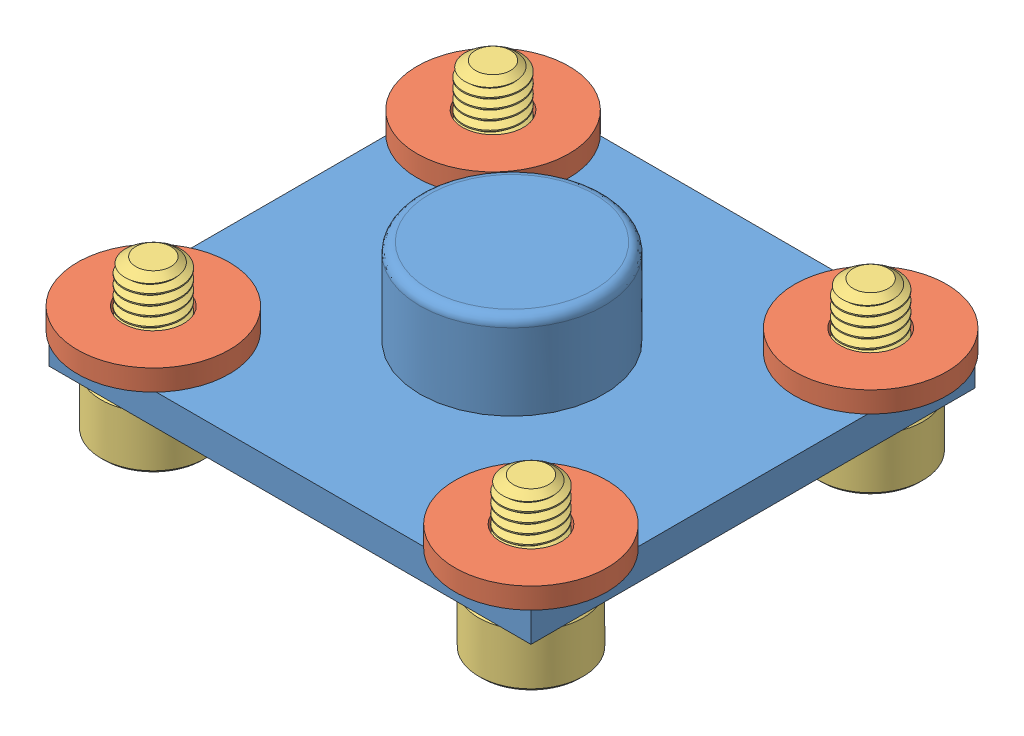
SolidWorks assembly Micro_withScrews, configuration Default. Lengths in mm.
Overall size (30.12 9.31 28.12).
9 component instances, 3 part files, 16 mates.
Components (placement in the parent):
- Micro-1: Micro [Default] at (8.9405 9.1432 20.4797) size (25.4 6.17 23.4)
- 95610A330_NYLON FLAT WASHER-2: 95610A330_NYLON FLAT WASHER [95610A330] at (18.8905 10.7832 29.4297) x (0.911056 0 -0.412283) z (0 1 0) size (8 8 1.1)
- 95610A330_NYLON FLAT WASHER-3: 95610A330_NYLON FLAT WASHER [95610A330] at (-1.0095 10.7832 29.4297) x (0.995756 0 -0.092036) z (0 1 0) size (8 8 1.1)
- 95610A330_NYLON FLAT WASHER-4: 95610A330_NYLON FLAT WASHER [95610A330] at (18.8905 10.7832 11.5297) x (0.992858 0 -0.119302) z (0 1 0) size (8 8 1.1)
- 95610A330_NYLON FLAT WASHER-5: 95610A330_NYLON FLAT WASHER [95610A330] at (-1.0095 10.7832 11.5297) x (0.963535 0 -0.267582) z (0 1 0) size (8 8 1.1)
- 91290A110_BLACK-OXIDE CLASS 12.9 SOCKET HEAD CAP SCREW-1: 91290A110_BLACK-OXIDE CLASS 12.9 SOCKET HEAD CAP SCREW [91290A110] at (-1.0095 14.1432 11.5297) x (0.69601 0 0.718032) z (0 1 0) size (5.5 5.5 8.18)
- 91290A110_BLACK-OXIDE CLASS 12.9 SOCKET HEAD CAP SCREW-2: 91290A110_BLACK-OXIDE CLASS 12.9 SOCKET HEAD CAP SCREW [91290A110] at (-1.0095 14.1432 29.4297) x (0.69601 0 0.718032) z (0 1 0) size (5.5 5.5 8.18)
- 91290A110_BLACK-OXIDE CLASS 12.9 SOCKET HEAD CAP SCREW-3: 91290A110_BLACK-OXIDE CLASS 12.9 SOCKET HEAD CAP SCREW [91290A110] at (18.8905 14.1432 11.5297) x (0.69601 0 0.718032) z (0 1 0) size (5.5 5.5 8.18)
- 91290A110_BLACK-OXIDE CLASS 12.9 SOCKET HEAD CAP SCREW-4: 91290A110_BLACK-OXIDE CLASS 12.9 SOCKET HEAD CAP SCREW [91290A110] at (18.8905 14.1432 29.4297) x (0.69601 0 0.718032) z (0 1 0) size (5.5 5.5 8.18)
Mates (geometry in assembly coordinates):
- Coincident1: coincident anti-aligned: plane of Micro-1 through (8.9405 10.7832 20.4797) normal (0 1 0); plane of 95610A330_NYLON FLAT WASHER-5 through (-1.0095 10.7832 11.5297) normal (0 -1 0)
- Coincident2: coincident anti-aligned: plane of Micro-1 through (8.9405 10.7832 20.4797) normal (0 1 0); plane of 95610A330_NYLON FLAT WASHER-3 through (-1.0095 10.7832 29.4297) normal (0 -1 0)
- Coincident3: coincident anti-aligned: plane of Micro-1 through (8.9405 10.7832 20.4797) normal (0 1 0); plane of 95610A330_NYLON FLAT WASHER-4 through (18.8905 10.7832 11.5297) normal (0 -1 0)
- Coincident4: coincident anti-aligned: plane of Micro-1 through (8.9405 10.7832 20.4797) normal (0 1 0); plane of 95610A330_NYLON FLAT WASHER-2 through (18.8905 10.7832 29.4297) normal (0 -1 0)
- Concentric1: concentric anti-aligned: cylinder of Micro-1 through (18.8905 9.1432 11.5297) axis (0 1 0) radius 1.75; cylinder of 95610A330_NYLON FLAT WASHER-4 through (18.8905 11.8832 11.5297) axis (0 -1 0) radius 1.6
- Concentric2: concentric anti-aligned: cylinder of Micro-1 through (-1.0095 9.1432 11.5297) axis (0 1 0) radius 1.75; cylinder of 95610A330_NYLON FLAT WASHER-5 through (-1.0095 11.8832 11.5297) axis (0 -1 0) radius 1.6
- Concentric3: concentric anti-aligned: cylinder of Micro-1 through (18.8905 9.1432 29.4297) axis (0 1 0) radius 1.75; cylinder of 95610A330_NYLON FLAT WASHER-2 through (18.8905 11.8832 29.4297) axis (0 -1 0) radius 1.6
- Concentric4: concentric anti-aligned: cylinder of Micro-1 through (-1.0095 9.1432 29.4297) axis (0 1 0) radius 1.75; cylinder of 95610A330_NYLON FLAT WASHER-3 through (-1.0095 11.8832 29.4297) axis (0 -1 0) radius 1.6
- Coincident7: coincident anti-aligned: plane of Micro-1 through (8.9405 9.1432 20.4797) normal (0 -1 0); plane of 91290A110_BLACK-OXIDE CLASS 12.9 SOCKET HEAD CAP SCREW-3 through (18.8905 9.1432 11.5297) normal (0 1 0)
- Coincident9: coincident anti-aligned: plane of Micro-1 through (8.9405 9.1432 20.4797) normal (0 -1 0); plane of 91290A110_BLACK-OXIDE CLASS 12.9 SOCKET HEAD CAP SCREW-4 through (18.8905 9.1432 29.4297) normal (0 1 0)
- Coincident10: coincident anti-aligned: plane of Micro-1 through (8.9405 9.1432 20.4797) normal (0 -1 0); plane of 91290A110_BLACK-OXIDE CLASS 12.9 SOCKET HEAD CAP SCREW-2 through (-1.0095 9.1432 29.4297) normal (0 1 0)
- Coincident11: coincident anti-aligned: plane of Micro-1 through (8.9405 9.1432 20.4797) normal (0 -1 0); plane of 91290A110_BLACK-OXIDE CLASS 12.9 SOCKET HEAD CAP SCREW-1 through (-1.0095 9.1432 11.5297) normal (0 1 0)
- Concentric5: concentric aligned: circle of 95610A330_NYLON FLAT WASHER-3; circle of 91290A110_BLACK-OXIDE CLASS 12.9 SOCKET HEAD CAP SCREW-2
- Concentric6: concentric aligned: circle of 95610A330_NYLON FLAT WASHER-5; circle of 91290A110_BLACK-OXIDE CLASS 12.9 SOCKET HEAD CAP SCREW-1
- Concentric7: concentric aligned: circle of 95610A330_NYLON FLAT WASHER-2; circle of 91290A110_BLACK-OXIDE CLASS 12.9 SOCKET HEAD CAP SCREW-4
- Concentric8: concentric aligned: circle of 95610A330_NYLON FLAT WASHER-4; circle of 91290A110_BLACK-OXIDE CLASS 12.9 SOCKET HEAD CAP SCREW-3
